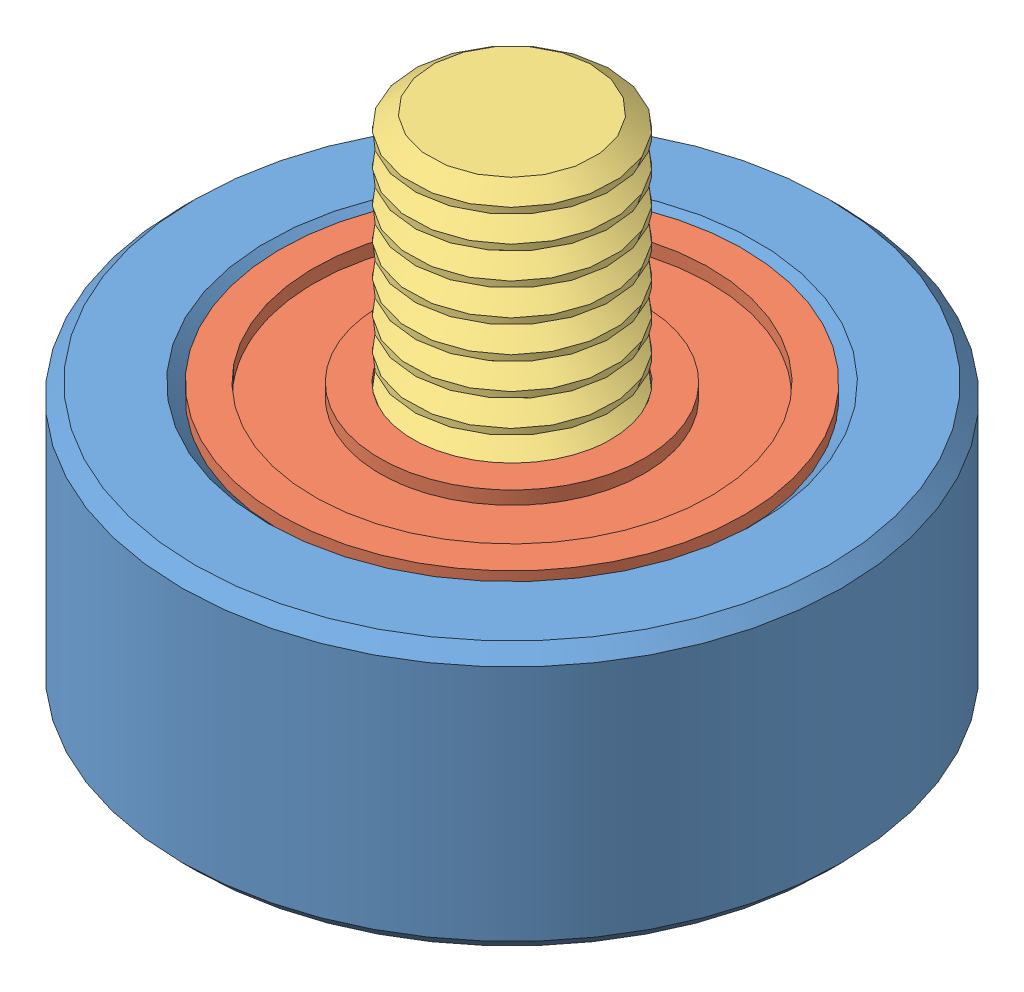
SolidWorks assembly tension roller, configuration Default. Lengths in mm.
Overall size (10 8 10).
3 component instances, 3 part files, 6 mates.
Components (placement in the parent):
- transmission belt tension roller-1: transmission belt tension roller [Default] at (2.5623 2.3439 8.8877) size (10 4 10)
- bearing 7mm x 3mm x 3mm-1: bearing 7mm x 3mm x 3mm [Default] at (2.5623 6.3439 8.8877) x (0.993894 0 0.110342) z (0 -1 0) size (7 7 3)
- flat head screw_am-1: flat head screw_am [B18.6.7M - M3 x 0.5 x 8 Type I Cross Recessed FHMS --8S] at (2.5623 1.8939 8.8877) x (0 1 0) z (0.646371 0 0.763024) size (8 5.5 5.5)
Mates (geometry in assembly coordinates):
- Concentric1: concentric anti-aligned: cylinder of transmission belt tension roller-1 through (2.5623 6.3439 8.8877) axis (0 -1 0) radius 3.5; cylinder of bearing 7mm x 3mm x 3mm-1 through (2.5623 3.3439 8.8877) axis (0 1 0) radius 3.5
- Coincident1: coincident anti-aligned: plane of transmission belt tension roller-1 through (2.5623 3.3439 8.8877) normal (0 1 0); plane of bearing 7mm x 3mm x 3mm-1 through (2.5623 3.3439 8.8877) normal (0 -1 0)
- Concentric2: concentric anti-aligned: cylinder of bearing 7mm x 3mm x 3mm-1 through (2.5623 3.3439 8.8877) axis (0 1 0) radius 1.5; cylinder of flat head screw_am-1 through (2.5623 -4.4561 8.8877) axis (0 -1 0) radius 1.5
- Concentric3: concentric anti-aligned: circle of transmission belt tension roller-1; circle of B18.6.7M - M3 x 0.5 x 8 Type I Cross Recessed FHMS --8S-1
- Concentric4: concentric anti-aligned: circle of transmission belt tension roller-1; circle of B18.6.7M - M3 x 0.5 x 8 Type I Cross Recessed FHMS --8S-1
- Coincident2: coincident aligned: plane of transmission belt tension roller-1 through (2.5623 2.3439 8.8877) normal (0 -1 0); circle of B18.6.7M - M3 x 0.5 x 8 Type I Cross Recessed FHMS --8S-1
